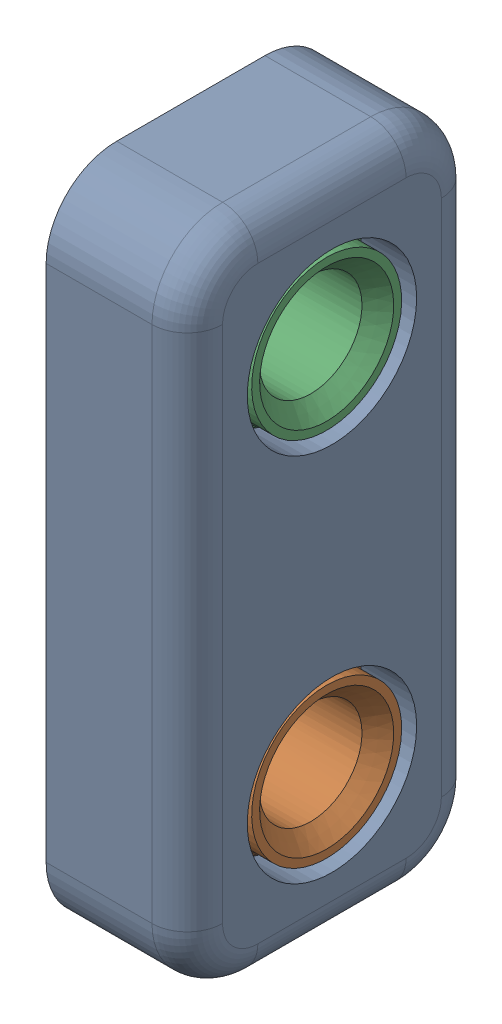
SolidWorks assembly probe_bracket, configuration Default. Lengths in mm.
Overall size (4 18.7 8.2).
3 component instances, 2 part files, 0 mates.
Components (placement in the parent):
- probe_bracket-1: probe_bracket [Default] at origin size (4 18.7 8.2)
- M3 Threaded Insert (1)-1: M3 Threaded Insert (1) [Default] at (-68.1791 123.292 -1.6573) x (0 1 0) z (-1 0 0) size (5 5 3.85)
- M3 Threaded Insert (1)-2: M3 Threaded Insert (1) [Default] at (-68.1791 133.792 -1.6573) x (0 1 0) z (-1 0 0) size (5 5 3.85)
